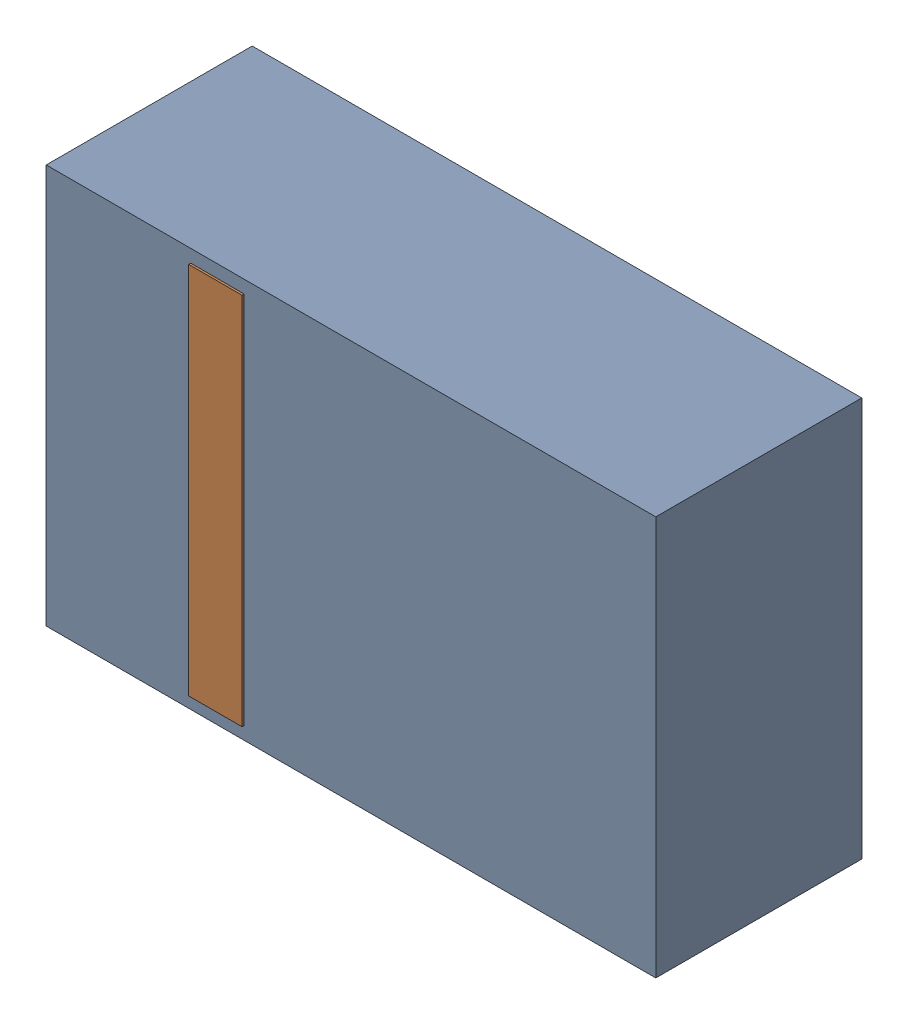
SolidWorks assembly D27, configuration Default. Lengths in mm.
Overall size (2.9 1.9 0.99).
4 component instances, 2 part files, 0 mates.
Components (placement in the parent):
- 905269392-1: 905269392 [Default] at (204.089 71.882 0) size (2.9 1.9 0.98)
  - Extruded_5-1: Extruded_5 [Default] at origin size (2.9 1.9 0.98)
- 905269800-1: 905269800 [Default] at (203.454 71.882 0.95) size (0.25 1.78 0.04)
  - Extruded_6-1: Extruded_6 [Default] at origin size (0.25 1.78 0.04)
